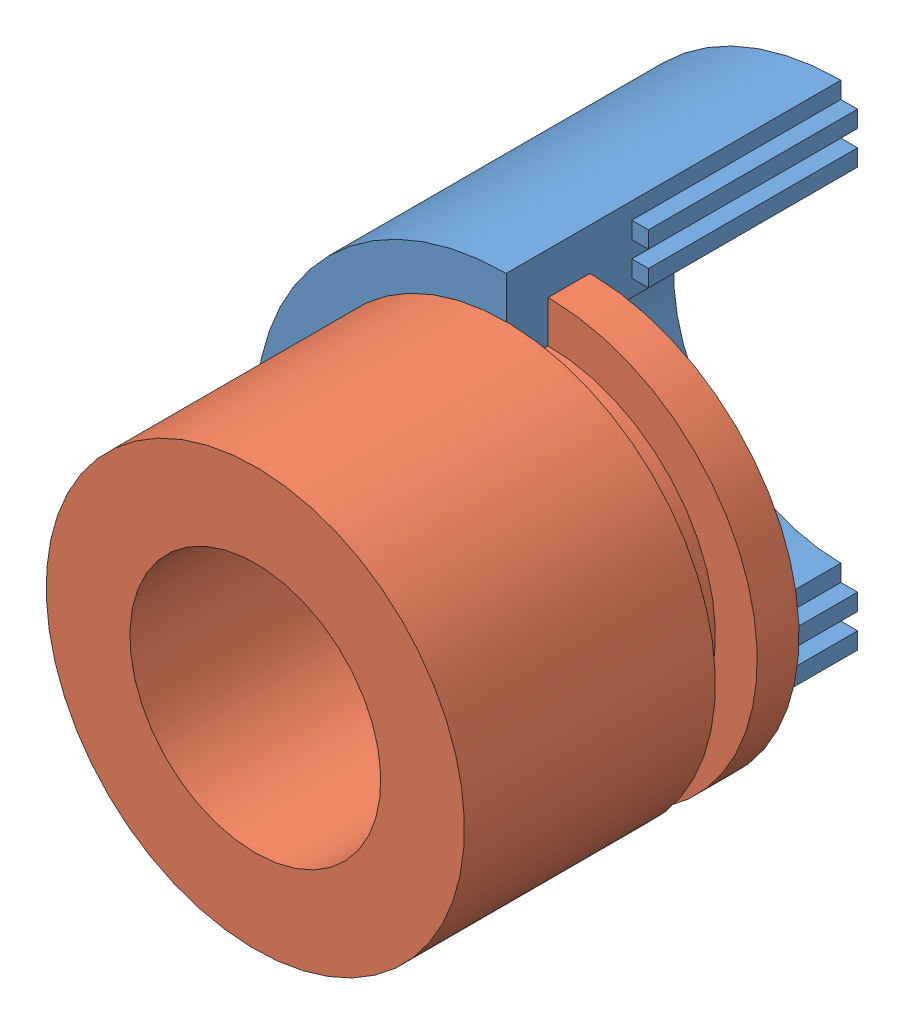
SolidWorks assembly Foreman rotation, configuration Default. Lengths in mm.
Overall size (142.39 152.4 177.8).
2 component instances, 2 part files, 2 mates.
Components (placement in the parent):
- Forearm rotation-1: Forearm rotation [Default] at (93.378 86.7687 60.7712) size (81.28 152.4 101.6)
- Foreman rotation 2-1: Foreman rotation 2 [Default] at (93.378 86.7687 238.5712) x (-0.999059 -0.043381 0) z (0 0 -1) size (127 127 101.6)
Mates (geometry in assembly coordinates):
- Concentric2: concentric aligned: circle of Forearm rotation-1; circle of Foreman rotation 2-1
- Coincident1: coincident anti-aligned: plane of Forearm rotation-1 through (93.378 86.7687 136.9712) normal (0 0 1); plane of Foreman rotation 2-1 through (93.378 86.7687 136.9712) normal (0 0 -1)
